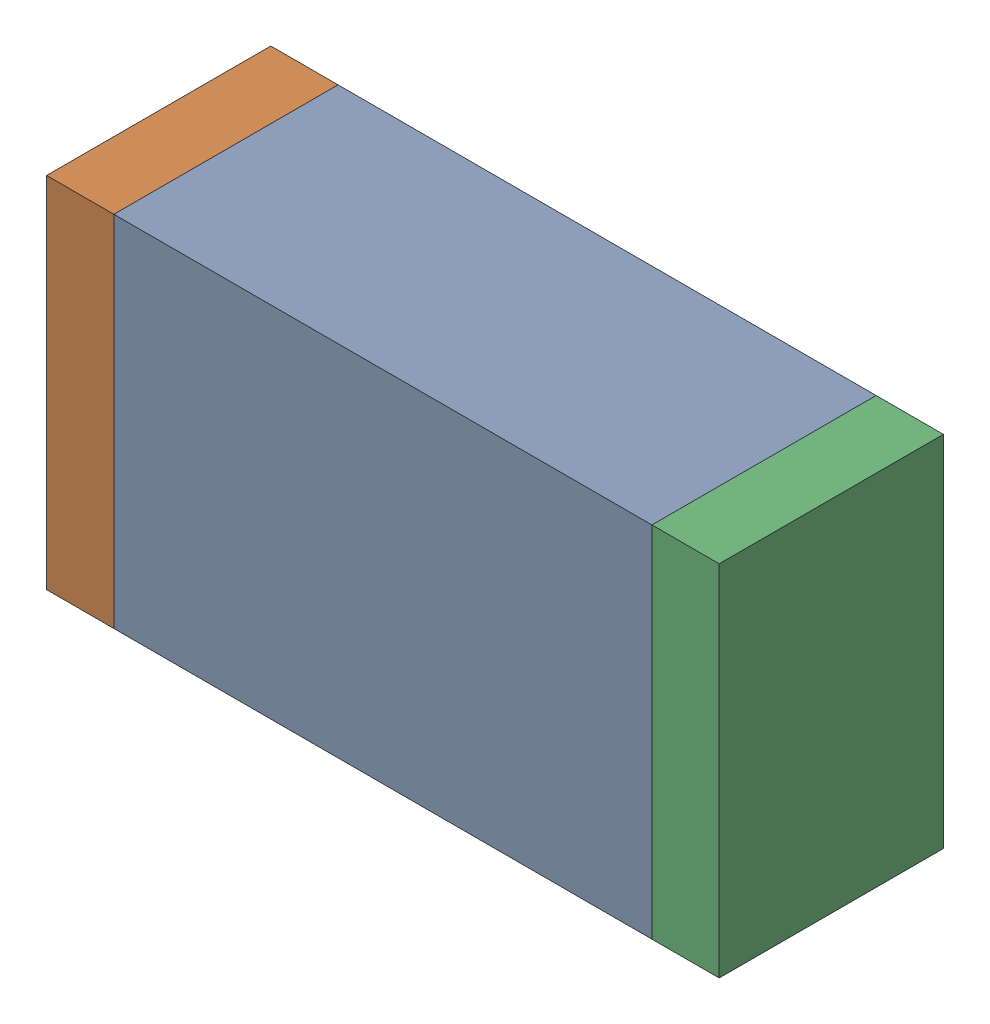
SolidWorks assembly D6, configuration Default. Lengths in mm.
Overall size (1.5 0.8 0.5).
6 component instances, 2 part files, 0 mates.
Components (placement in the parent):
- 836752368-1: 836752368 [Default] at (111.15 14.05 0) size (1.2 0.8 0.5)
  - Extruded-1: Extruded [Default] at origin size (1.2 0.8 0.5)
- 836752496-1: 836752496 [Default] at (110.475 14.05 0) size (0.15 0.8 0.5)
  - Extruded_2-1: Extruded_2 [Default] at origin size (0.15 0.8 0.5)
- 836752496-2: 836752496 [Default] at (111.825 14.05 0) size (0.15 0.8 0.5)
  - Extruded_2-1: Extruded_2 [Default] at origin size (0.15 0.8 0.5)
